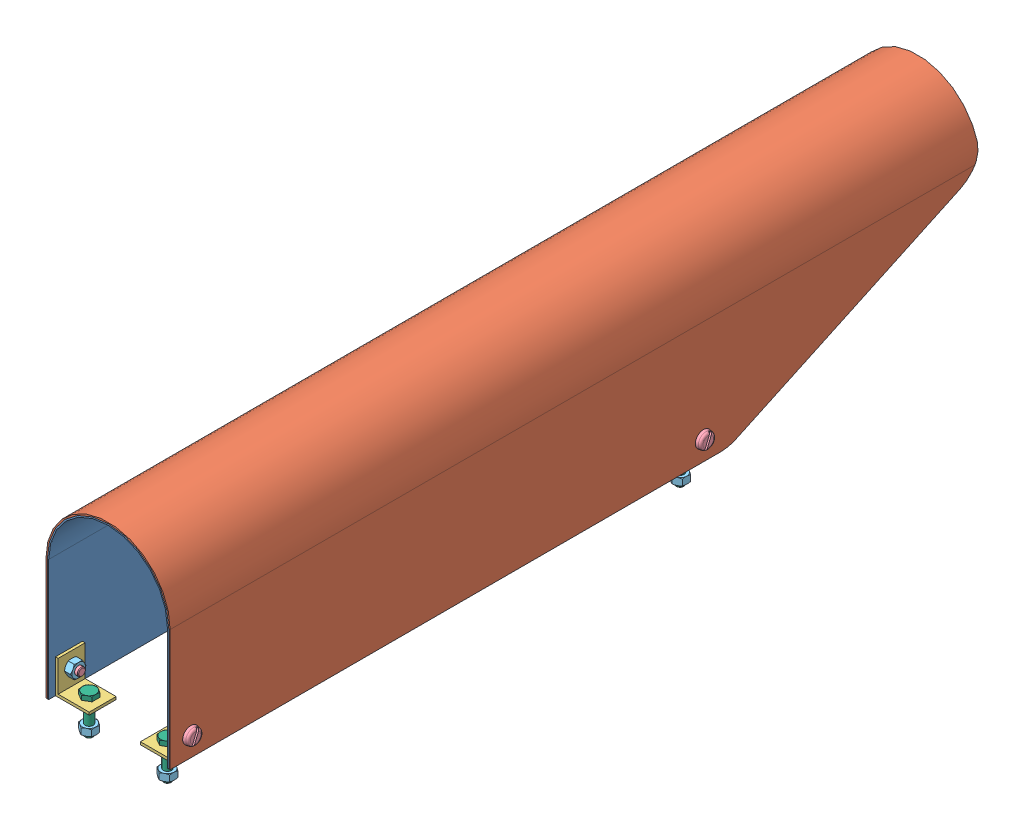
SolidWorks assembly Heat protection Assembly, configuration Default. Lengths in mm.
Overall size (100.02 159 600).
26 component instances, 6 part files, 23 mates.
Components (placement in the parent):
- Heat isolant-1: Heat isolant [Default] at (111.0083 421.5761 700.2699) size (90 135 600)
- Heat protection-2: Heat protection [Default] at (111.0083 421.5761 700.2699) size (92 136 600)
- ASM Square-1: ASM Square [Default] at (67.0083 421.5761 685.2699) size (31.01 48 20)
  - Square-1: Square [Default] at origin size (25 25 20)
  - Screw M6X12-1: Screw M6X12 [Default] at (-5.9 15 0) x (0 -0.924225 -0.381849) z (1 0 0) size (12 12 15.71)
  - Nut HM6-1: Nut HM6 [Default] at (7.2 15 0) x (0 0 1) z (-1 0 0) size (11.55 10 5.2)
  - Nut HM6-2: Nut HM6 [Default] at (15 -20.2 0) x (0.837169 0 0.546944) z (0 1 0) size (11.55 10 5.2)
  - Screw M6X25-1: Screw M6X25 [Default] at (15 2 0) x (1 0 0) z (0 -1 0) size (10 11.55 29)
- ASM Square-2: ASM Square [Default] at (67.0083 421.5761 305.2699) size (31.01 48 20)
  - Square-1: Square [Default] at origin size (25 25 20)
  - Screw M6X12-1: Screw M6X12 [Default] at (-5.9 15 0) x (0 -0.924225 -0.381849) z (1 0 0) size (12 12 15.71)
  - Nut HM6-1: Nut HM6 [Default] at (7.2 15 0) x (0 0 1) z (-1 0 0) size (11.55 10 5.2)
  - Nut HM6-2: Nut HM6 [Default] at (15 -20.2 0) x (0.837169 0 0.546944) z (0 1 0) size (11.55 10 5.2)
  - Screw M6X25-1: Screw M6X25 [Default] at (15 2 0) x (1 0 0) z (0 -1 0) size (10 11.55 29)
- ASM Square-4: ASM Square [Default] at (155.0083 421.5761 685.2699) x (-1 0 0) z (0 0 -1) size (31.01 48 20)
  - Square-1: Square [Default] at origin size (25 25 20)
  - Screw M6X12-1: Screw M6X12 [Default] at (-5.9 15 0) x (0 -0.924225 -0.381849) z (1 0 0) size (12 12 15.71)
  - Nut HM6-1: Nut HM6 [Default] at (7.2 15 0) x (0 0 1) z (-1 0 0) size (11.55 10 5.2)
  - Nut HM6-2: Nut HM6 [Default] at (15 -20.2 0) x (0.837169 0 0.546944) z (0 1 0) size (11.55 10 5.2)
  - Screw M6X25-1: Screw M6X25 [Default] at (15 2 0) x (1 0 0) z (0 -1 0) size (10 11.55 29)
- ASM Square-6: ASM Square [Default] at (155.0083 421.5761 305.2699) x (-1 0 0) z (0 0 -1) size (31.01 48 20)
  - Square-1: Square [Default] at origin size (25 25 20)
  - Screw M6X12-1: Screw M6X12 [Default] at (-5.9 15 0) x (0 -0.924225 -0.381849) z (1 0 0) size (12 12 15.71)
  - Nut HM6-1: Nut HM6 [Default] at (7.2 15 0) x (0 0 1) z (-1 0 0) size (11.55 10 5.2)
  - Nut HM6-2: Nut HM6 [Default] at (15 -20.2 0) x (0.837169 0 0.546944) z (0 1 0) size (11.55 10 5.2)
  - Screw M6X25-1: Screw M6X25 [Default] at (15 2 0) x (1 0 0) z (0 -1 0) size (10 11.55 29)
Mates (geometry in assembly coordinates):
- Coincident1: coincident: plane of Heat isolant-1 through (67.0083 421.5761 100.2699) normal (1 0 0); plane of ASM Square-1/Square-1 through (67.0083 446.5761 695.2699) normal (-1 0 0)
- Concentric1: concentric: cylinder of Heat isolant-1 through (156.0083 436.5761 685.2699) axis (-1 0 0) radius 4; cylinder of ASM Square-1/Square-1 through (69.0083 436.5761 685.2699) axis (1 0 0) radius 4
- Coincident2: coincident: plane of Heat isolant-1 through (67.0083 421.5761 100.2699) normal (1 0 0); plane of ASM Square-1/Square-1 through (67.0083 446.5761 695.2699) normal (-1 0 0)
- Concentric3: concentric: cylinder of Heat isolant-1 through (156.0083 433.5761 685.2699) axis (-1 0 0) radius 4; cylinder of ASM Square-4/Square-1 through (153.0083 433.5761 685.2699) axis (-1 0 0) radius 4
- Coincident4: coincident: plane of Heat isolant-1 through (155.0083 511.5761 100.2699) normal (-1 0 0); plane of ASM Square-4/Square-1 through (155.0083 441.5761 675.2699) normal (1 0 0)
- Coincident6: coincident: plane of Heat isolant-1 through (67.0083 421.5761 100.2699) normal (1 0 0); plane of ? through (67.0083 441.5761 275.2699) normal (-1 0 0)
- Concentric4: concentric: cylinder of Heat isolant-1 through (156.0083 433.5761 265.2699) axis (-1 0 0) radius 4; cylinder of ? through (69.0083 433.5761 265.2699) axis (1 0 0) radius 4
- Concentric5: concentric: cylinder of Heat isolant-1 through (156.0083 433.5761 265.2699) axis (-1 0 0) radius 4; cylinder of ? through (153.0083 433.5761 265.2699) axis (-1 0 0) radius 4
- Coincident7: coincident: plane of Heat isolant-1 through (155.0083 511.5761 100.2699) normal (-1 0 0); plane of ? through (155.0083 421.5761 275.2699) normal (1 0 0)
- Coincident8: coincident: plane of ? through (67.0083 421.5761 275.2699) normal (0 -1 0); plane of ? through (135.0083 421.5761 275.2699) normal (0 -1 0)
- Coincident11: coincident: plane of Heat isolant-1 through (156.0083 421.5761 100.2699) normal (0 -1 0); plane of ASM Square-4/Square-1 through (155.0083 421.5761 675.2699) normal (0 -1 0)
- Coincident12: coincident: plane of Heat isolant-1 through (67.0083 421.5761 100.2699) normal (0 -1 0); plane of ? through (67.0083 421.5761 275.2699) normal (0 -1 0)
- Coincident13: coincident: point of Heat protection-2; point of Heat isolant-1
- Coincident14: coincident: plane of Heat isolant-1 through (67.0083 421.5761 100.2699) normal (0 -1 0); plane of ASM Square-1/Square-1 through (67.0083 421.5761 695.2699) normal (0 -1 0)
- Coincident15: coincident: plane of Heat isolant-1 through (67.0083 421.5761 100.2699) normal (1 0 0); plane of ASM Square-2/Square-1 through (67.0083 446.5761 315.2699) normal (-1 0 0)
- Concentric6: concentric: cylinder of Heat isolant-1 through (156.0083 436.5761 305.2699) axis (-1 0 0) radius 4; cylinder of ASM Square-2/Square-1 through (69.0083 436.5761 305.2699) axis (1 0 0) radius 4
- Coincident22: coincident: plane of Heat isolant-1 through (67.0083 421.5761 100.2699) normal (0 -1 0); plane of ASM Square-2/Square-1 through (67.0083 421.5761 315.2699) normal (0 -1 0)
- Coincident23: coincident: plane of Heat isolant-1 through (155.0083 511.5761 100.2699) normal (-1 0 0); plane of ASM Square-4/Square-1 through (155.0083 446.5761 675.2699) normal (1 0 0)
- Concentric9: concentric: cylinder of Heat isolant-1 through (156.0083 436.5761 685.2699) axis (-1 0 0) radius 4; cylinder of ASM Square-4/Square-1 through (153.0083 436.5761 685.2699) axis (-1 0 0) radius 4
- Coincident24: coincident: plane of Heat isolant-1 through (67.0083 421.5761 100.2699) normal (0 -1 0); plane of ASM Square-4/Square-1 through (155.0083 421.5761 675.2699) normal (0 -1 0)
- Coincident25: coincident: plane of Heat isolant-1 through (155.0083 511.5761 100.2699) normal (-1 0 0); plane of ASM Square-6/Square-1 through (155.0083 446.5761 295.2699) normal (1 0 0)
- Concentric10: concentric: cylinder of Heat isolant-1 through (156.0083 436.5761 305.2699) axis (-1 0 0) radius 4; cylinder of ASM Square-6/Square-1 through (153.0083 436.5761 305.2699) axis (-1 0 0) radius 4
- Coincident26: coincident: plane of Heat protection-2 through (157.0083 421.5761 100.2699) normal (0 -1 0); plane of ASM Square-6/Square-1 through (155.0083 421.5761 295.2699) normal (0 -1 0)
